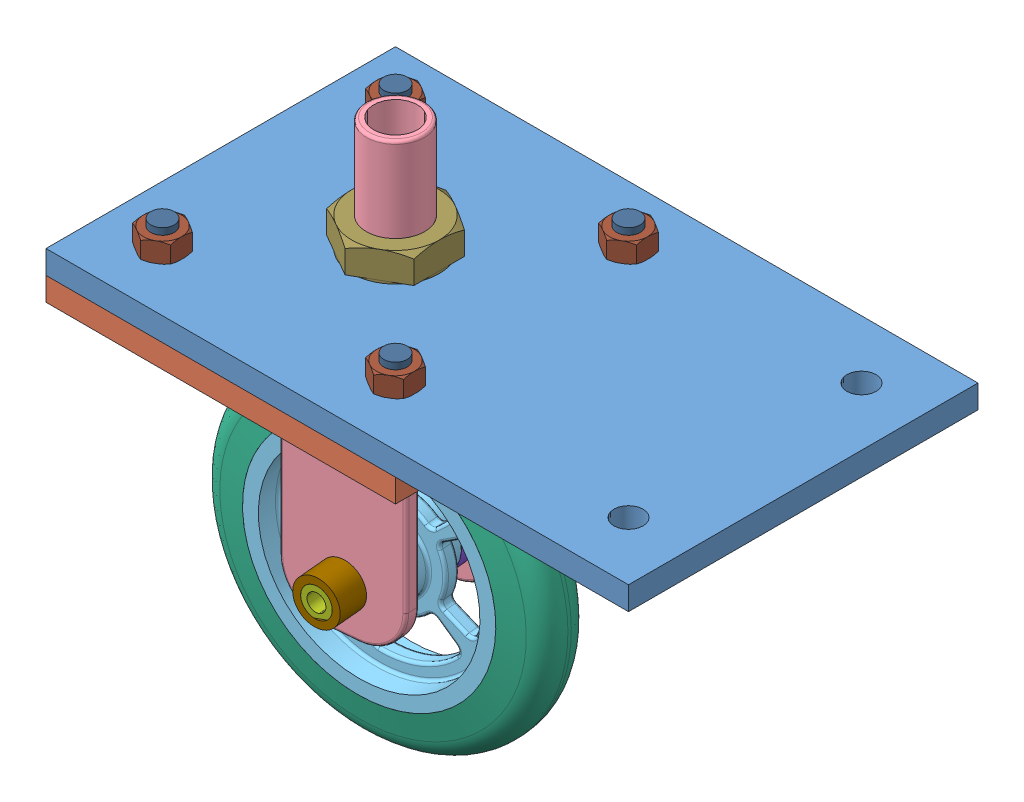
SolidWorks assembly final assembly, configuration Default. Lengths in mm.
Overall size (216.01 201.58 120).
22 component instances, 13 part files, 21 mates.
Components (placement in the parent):
- Base.SLDPART.-2: Base.SLDPART. [Default] at (-67.2248 121.9152 -5.3212) size (200 8 120)
- Mount.SLDPART-1: Mount.SLDPART [Default] at (-67.2248 113.9152 -5.3212) x (0 0 -1) z (1 0 0) size (120 8 120)
- Bearing.SLDPART-1: Bearing.SLDPART [Default] at (-67.2248 113.9152 -5.3212) x (0.853471 0 0.521141) z (0 -1 0) size (30 30 5)
- Fork.SLDPART-1: Fork.SLDPART [Default] at (-67.2248 108.9152 -5.3212) x (-0.995838 0 0.091142) z (0.091142 0 0.995838) size (80 143 80)
- Wheel and Axel.2-1: Wheel and Axel.2 [Default] at (-143.0277 62.6394 -21.8964) x (0.091142 0 0.995838) z (0.938826 0.3335 -0.085925) size (60 115.31 115.31)
  - Wheel.SLDPART-1: Wheel.SLDPART [Default] at (23.415 45.1517 62.4965) size (20 80 80)
  - Tire.SLDPART-1: Tire.SLDPART [Default] at (23.415 45.1517 62.4965) x (1 0 0) z (0 -0.049481 0.998775) size (20 110 110)
  - Axel.SLDPART-1: Axel.SLDPART [Default] at (23.415 45.1517 62.4965) x (0 -0.050219 -0.998738) z (1 0 0) size (10 10 60)
  - Washer.SLDPART-1: Washer.SLDPART [Default] at (8.415 45.1517 62.4965) x (0 -0.153708 -0.988116) z (0 -0.988116 0.153708) size (25 5 25)
  - Washer.SLDPART-2: Washer.SLDPART [Default] at (38.415 45.1517 62.4965) x (0 0.906189 0.422872) z (0 -0.422872 0.906189) size (25 5 25)
- Collar.SLDPART-1: Collar.SLDPART [Default] at (-64.9463 40.9152 19.5747) x (0.95432 0.285735 -0.087343) z (0.091142 0 0.995838) size (15 15 10)
- Collar.SLDPART-2: Collar.SLDPART [Default] at (-69.5034 40.9152 -30.2172) x (-0.95432 -0.285735 0.087343) z (-0.091142 0 -0.995838) size (15 15 10)
- hex screw_am-8: hex screw_am [B18.6.7M - M8 x 1.25 x 25 Indented HHMS --25N] at (-107.2248 107.9152 -45.3212) x (0 1 0) z (0 0 1) size (31 15.01 13)
- hex nut style 1_am-4: hex nut style 1_am [B18.2.4.1M - Hex nut, Style 1,  M8 x 1.25 --D-N] at (-107.2248 129.8511 -45.3212) x (1 0 0) z (0 -1 0) size (13 15.01 6.8)
- hex nut style 1_am-5: hex nut style 1_am [B18.2.4.1M - Hex nut, Style 1,  M8 x 1.25 --D-N] at (-27.2248 129.8511 -45.3212) x (1 0 0) z (0 -1 0) size (13 15.01 6.8)
- hex nut style 1_am-6: hex nut style 1_am [B18.2.4.1M - Hex nut, Style 1,  M8 x 1.25 --D-N] at (-107.2248 129.8511 34.6788) x (1 0 0) z (0 -1 0) size (13 15.01 6.8)
- hex nut style 1_am-7: hex nut style 1_am [B18.2.4.1M - Hex nut, Style 1,  M8 x 1.25 --D-N] at (-27.2248 129.8511 34.6788) x (1 0 0) z (0 -1 0) size (13 15.01 6.8)
- hex screw_am-9: hex screw_am [B18.6.7M - M8 x 1.25 x 25 Indented HHMS --25N] at (-27.2248 107.9152 -45.3212) x (0 1 0) z (0 0 1) size (31 15.01 13)
- hex screw_am-10: hex screw_am [B18.6.7M - M8 x 1.25 x 25 Indented HHMS --25N] at (-107.2248 107.9152 34.6788) x (0 1 0) z (0 0 1) size (31 15.01 13)
- hex screw_am-11: hex screw_am [B18.6.7M - M8 x 1.25 x 25 Indented HHMS --25N] at (-27.2248 107.9152 34.6788) x (0 1 0) z (0 0 1) size (31 15.01 13)
- hex nut jam_am-3: hex nut jam_am [B18.2.4.5M - Hex jam nut,  M20 x 2.5 --W-N] at (-67.2248 139.9152 -5.3212) x (1 0 0) z (0 1 0) size (30 34.64 10)
- socket set screw flat point_am-6: socket set screw flat point_am [PreviewCfg] at (-68.9173 40.9152 -23.8133) x (0.091142 0 0.995838) z (-0.995838 0 0.091142) size (3 5 5)
Mates (geometry in assembly coordinates):
- Coincident2: coincident anti-aligned: plane of Base.SLDPART.-2 through (-67.2248 121.9152 -5.3212) normal (0 -1 0); plane of Mount.SLDPART-1 through (-67.2248 121.9152 -5.3212) normal (0 1 0)
- Coincident3: coincident aligned: circle of Base.SLDPART.-2; circle of Mount.SLDPART-1
- Coincident4: coincident aligned: circle of Base.SLDPART.-2; circle of Mount.SLDPART-1
- Coincident5: coincident anti-aligned: plane of Mount.SLDPART-1 through (-67.2248 113.9152 -5.3212) normal (0 -1 0); plane of Bearing.SLDPART-1 through (-67.2248 113.9152 -5.3212) normal (0 1 0)
- Concentric1: concentric anti-aligned: circle of Mount.SLDPART-1; circle of Bearing.SLDPART-1
- Coincident8: coincident anti-aligned: plane of Bearing.SLDPART-1 through (-67.2248 108.9152 -5.3212) normal (0 -1 0); plane of Fork.SLDPART-1 through (-67.2248 108.9152 -5.3212) normal (0 1 0)
- Coincident9: coincident anti-aligned: circle of Bearing.SLDPART-1; circle of Fork.SLDPART-1
- Coincident13: coincident: plane of Fork.SLDPART-1 through (-65.8577 25.9152 9.6164) normal (-0.091142 0 -0.995838); plane of Wheel and Axel.2-1/Washer.SLDPART-2 through (-65.8577 40.9152 9.6164) normal (0.091142 0 0.995838)
- Concentric2: concentric: cylinder of Fork.SLDPART-1 through (-62.1208 40.9152 50.4457) axis (-0.091142 0 -0.995838) radius 5; cylinder of Wheel and Axel.2-1/Axel.SLDPART-1 through (-64.4905 40.9152 24.5539) axis (-0.091142 0 -0.995838) radius 3
- Coincident15: coincident: plane of Fork.SLDPART-1 through (-69.0477 25.9152 -25.238) normal (-0.091142 0 -0.995838); plane of Collar.SLDPART-2 through (-69.0477 40.9152 -25.238) normal (0.091142 0 0.995838)
- Coincident18: coincident: circle of Fork.SLDPART-1; circle of Collar.SLDPART-2
- Parallel4: parallel: plane of Wheel and Axel.2-1/Axel.SLDPART-1 through (-67.2248 40.9152 -5.3212) normal (-0.95432 -0.285735 0.087343); plane of Collar.SLDPART-2 through (-69.5034 40.9152 -30.2172) normal (-0.95432 -0.285735 0.087343)
- Coincident20: coincident: plane of Fork.SLDPART-1 through (-65.402 25.9152 14.5955) normal (0.091142 0 0.995838); plane of Collar.SLDPART-1 through (-65.402 40.9152 14.5955) normal (-0.091142 0 -0.995838)
- Coincident21: coincident: circle of Fork.SLDPART-1; circle of Collar.SLDPART-1
- Parallel5: parallel: plane of Wheel and Axel.2-1/Axel.SLDPART-1 through (-67.2248 40.9152 -5.3212) normal (-0.95432 -0.285735 0.087343); plane of Collar.SLDPART-1 through (-64.9463 40.9152 19.5747) normal (0.95432 0.285735 -0.087343)
- Concentric6: concentric anti-aligned: cylinder of Mount.SLDPART-1 through (-107.2248 113.9152 -45.3212) axis (0 1 0) radius 5; cylinder of hex screw_am-8 through (-107.2248 82.5152 -45.3212) axis (0 -1 0) radius 4
- Coincident22: coincident anti-aligned: plane of Mount.SLDPART-1 through (-67.2248 113.9152 -5.3212) normal (0 -1 0); plane of hex screw_am-8 through (-111.2248 113.9152 -45.3212) normal (0 1 0)
- Concentric9: concentric aligned: cylinder of hex screw_am-8 through (-107.2248 82.5152 -45.3212) axis (0 -1 0) radius 4; cylinder of hex nut style 1_am-4 through (-107.2248 154.8886 -45.3212) axis (0 -1 0) radius 4
- Concentric12: concentric aligned: cylinder of Base.SLDPART.-2 through (-67.2248 119.9152 -5.3212) axis (0 1 0) radius 12.5; cylinder of hex nut jam_am-3 through (-67.2248 114.8777 -5.3212) axis (0 1 0) radius 10
- Coincident24: coincident anti-aligned: plane of Base.SLDPART.-2 through (-67.2248 129.9152 -5.3212) normal (0 1 0); plane of hex nut jam_am-3 through (-67.2248 129.9152 -22.6417) normal (0 -1 0)
- Concentric161: concentric aligned: cylinder of Wheel and Axel.2-1/Axel.SLDPART-1 through (-64.4905 40.9152 24.5539) axis (-0.091142 0 -0.995838) radius 3; cylinder of socket set screw flat point_am-6 through (-70.0748 40.9152 -36.4605) axis (-0.091142 0 -0.995838) radius 2.5
